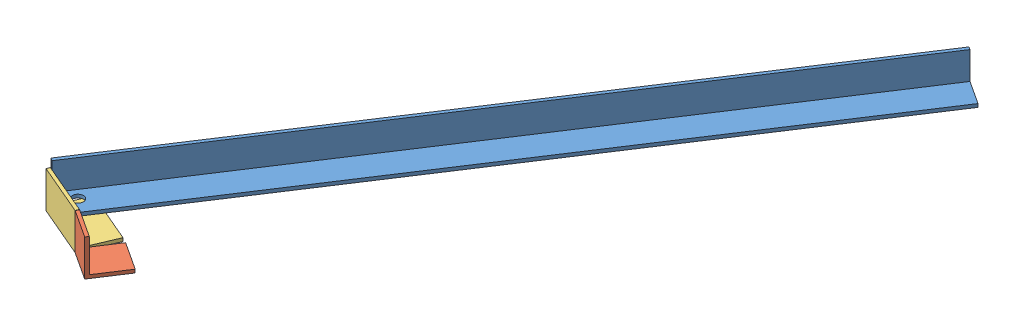
SolidWorks assembly НогаПСБ, configuration По умолчанию. Lengths in mm.
Overall size (353.59 36.25 552.81).
4 component instances, 3 part files, 2 mates.
Components (placement in the parent):
- Нога1п-1: Нога1п [По умолчанию] at (445.7806 11.1853 -189.4622) x (0.837169 0 0.546944) z (-0.546944 0 0.837169) size (28 28 600)
- КрП-1: КрП [По умолчанию] at (154.4762 6.7623 319.5277) x (0.546944 0 -0.837169) z (0.837169 0 0.546944) size (41.68 33 84.97)
  - Кр1П-1: Кр1П [По умолчанию] at (-7.3427 -3.8242 48) size (33 33 30)
  - Кр2П-1: Кр2П [По умолчанию] at (-7.3882 -3.8242 17.4791) x (0.984808 0 -0.173648) z (0.173648 0 0.984808) size (33 33 50)
Mates (geometry in assembly coordinates):
- Концентричный1: concentric aligned: cylinder of Нога1п-1 through (134.19 18.1853 305.7511) axis (0 -1 0) radius 5; cylinder of КрП-1/Кр2П-1 through (134.19 9.9381 305.7511) axis (0 -1 0) radius 5
- Угол1: planar angle = 1.396263 rad aligned: plane of Нога1п-1 through (115.1026 36.1853 311.1984) normal (-0.837169 0 -0.546944); plane of КрП-1/Кр2П-1 through (119.0968 32.9381 315.6099) normal (0.393262 0 -0.919426)
